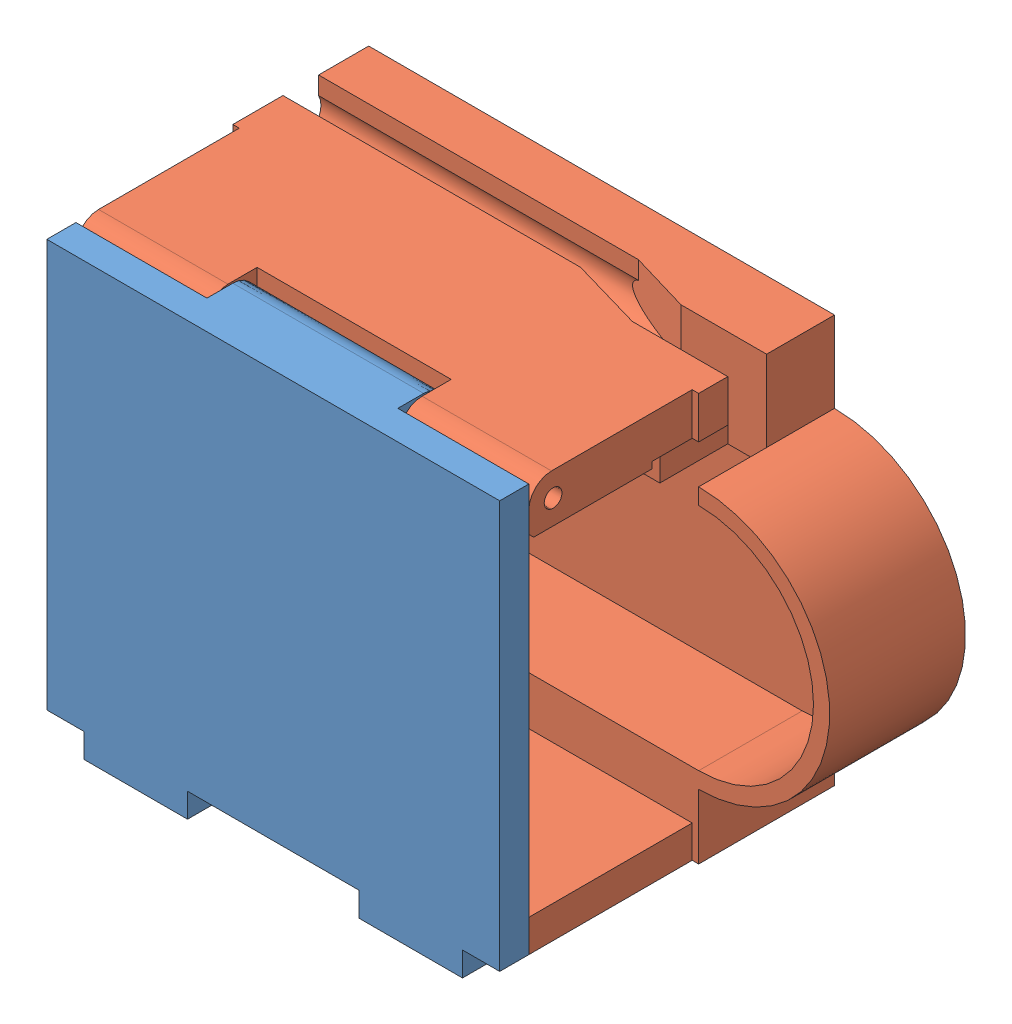
SolidWorks assembly 装配体1, configuration Default. Lengths in mm.
Overall size (45 26.7 20.3).
2 component instances, 2 part files, 3 mates.
Components (placement in the parent):
- 盖子-1: 盖子 [Default] at (-6.7664 -32.7923 45.6379) x (1 0 0) z (0 0 -1) size (28 26.7 5.4)
- 零件1-1: 零件1 [Default] at (-15.2664 -32.7923 25.3379) x (0 1 0) z (0 0 1) size (25.2 45 18.5)
Mates (geometry in assembly coordinates):
- 同心1: concentric aligned: cylinder of 盖子-1 through (-6.7664 -9.0923 42.3379) axis (1 0 0) radius 0.55; cylinder of 零件1-1 through (-4.7664 -9.0923 42.3379) axis (1 0 0) radius 0.55
- 距离2: distance = 0.1 mm anti-aligned: plane of 零件1-1 through (13.2336 -10.5923 40.6379) normal (-1 0 0); plane of 盖子-1 through (13.1336 -7.5923 40.8379) normal (1 0 0)
- LimitAngle1: limit planar angle = 0 rad anti-aligned: plane of 盖子-1 through (-6.7664 -32.7923 43.8379) normal (0 0 -1); plane of 零件1-1 through (-15.2664 -32.7923 43.8379) normal (0 0 1)
